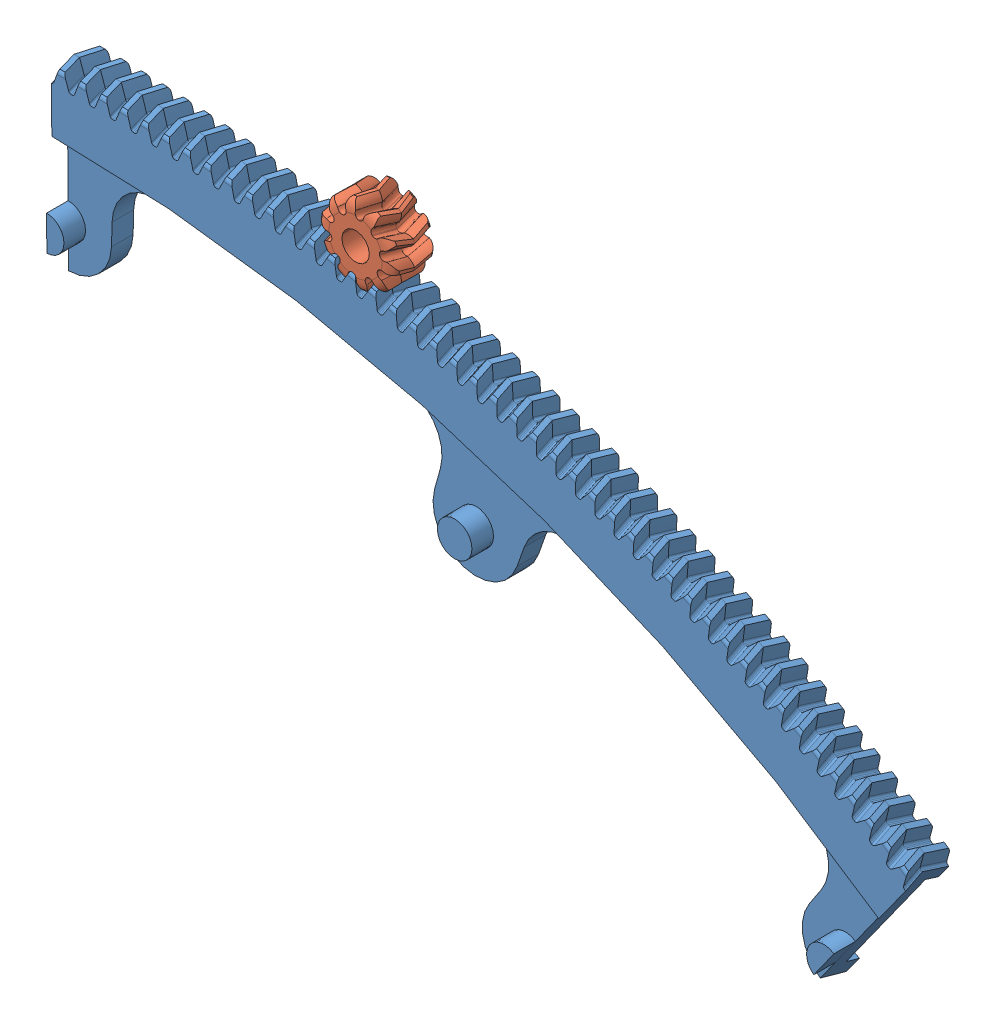
SolidWorks assembly Assem1, configuration Default. Lengths in mm.
Overall size (199.65 111.22 10.77).
2 component instances, 2 part files, 2 mates.
Components (placement in the parent):
- 450 Teeth Section-1: 450 Teeth Section [Gear Blank] at (-63.6287 441.7873 664.3949) size (199.65 99.73 10.72)
- Motor Gear-1: Motor Gear [Gear Blank] at (5.0297 779.8864 664.3949) x (0.738804 0.673921 0) z (0 0 1) size (17.92 18.06 10.77)
Mates (geometry in assembly coordinates):
- Coincident1: coincident aligned: plane of 450 Teeth Section-1 through (-63.9353 780.1229 674.3949) normal (0 0 1); plane of Motor Gear-1 through (-1.6176 785.0372 674.3949) normal (0 0 1)
- Distance1: distance = 345 mm: point of Motor Gear-1; point of 450 Teeth Section-1
